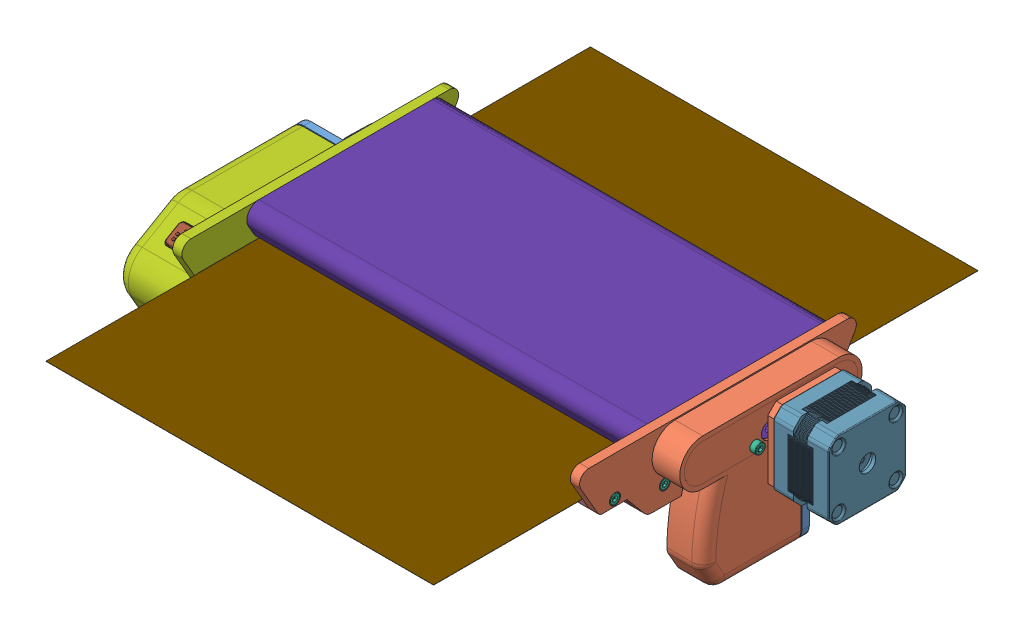
SolidWorks assembly Brailleprinter, configuration Default. Lengths in mm.
Overall size (310 78.25 295).
134 component instances, 36 part files, 16 mates.
Components (placement in the parent):
- Frame-2: Frame [Default] at (6.5066 -52.4976 -87.3723) size (276.5 62.15 134.33)
  - Frame plate-1: Frame plate [Default] at (76.4618 160.0978 166.7235) size (276.5 61.25 5)
  - Linear rail-1: Linear rail [Default] at (70.7618 160.0978 171.7235) x (0 1 0) z (1 0 0) size (9 6.5 208.9)
  - Motor plate-1: Motor plate [Default] at (46.4618 139.3516 166.7235) x (-1 0 0) z (0 0 -1) size (61.5 53.5 20.15)
  - Paper tray-1: Paper tray [Default] at (175.2118 177.0978 267.3903) x (0 0 -1) z (1 0 0) size (134.33 22 210.5)
  - Limit switch-1: Limit switch [Default] at (79.6118 165.8978 235.3903) x (0 0 -1) z (1 0 0) size (20.1 16 6.3)
  - socket head cap screw_din-1: socket head cap screw_din [DIN 912 M3 x 12 --- 12N] at (76.4618 160.0978 177.7235) x (0 0 -1) z (1 0 0) size (15 5.5 5.5)
  - socket head cap screw_din-2: socket head cap screw_din [DIN 912 M3 x 12 --- 12N] at (96.4618 160.0978 177.7235) x (0 0 -1) z (1 0 0) size (15 5.5 5.5)
  - socket head cap screw_din-3: socket head cap screw_din [DIN 912 M3 x 12 --- 12N] at (116.4618 160.0978 177.7235) x (0 0 -1) z (1 0 0) size (15 5.5 5.5)
  - socket head cap screw_din-4: socket head cap screw_din [DIN 912 M3 x 12 --- 12N] at (136.4618 160.0978 177.7235) x (0 0 -1) z (1 0 0) size (15 5.5 5.5)
  - socket head cap screw_din-5: socket head cap screw_din [DIN 912 M3 x 12 --- 12N] at (156.4618 160.0978 177.7235) x (0 0 -1) z (1 0 0) size (15 5.5 5.5)
  - socket head cap screw_din-6: socket head cap screw_din [DIN 912 M3 x 12 --- 12N] at (176.4618 160.0978 177.7235) x (0 0 -1) z (1 0 0) size (15 5.5 5.5)
  - socket head cap screw_din-7: socket head cap screw_din [DIN 912 M3 x 12 --- 12N] at (196.4618 160.0978 177.7235) x (0 0 -1) z (1 0 0) size (15 5.5 5.5)
  - socket head cap screw_din-8: socket head cap screw_din [DIN 912 M3 x 12 --- 12N] at (216.4618 160.0978 177.7235) x (0 0 -1) z (1 0 0) size (15 5.5 5.5)
  - socket head cap screw_din-9: socket head cap screw_din [DIN 912 M3 x 12 --- 12N] at (236.4618 160.0978 177.7235) x (0 0 -1) z (1 0 0) size (15 5.5 5.5)
  - socket head cap screw_din-10: socket head cap screw_din [DIN 912 M3 x 12 --- 12N] at (256.4618 160.0978 177.7235) x (0 0 -1) z (1 0 0) size (15 5.5 5.5)
  - socket head cap screw_din-11: socket head cap screw_din [DIN 912 M3 x 8 --- 8N] at (276.4618 160.0978 177.7235) x (0 0 -1) z (1 0 0) size (11 5.5 5.5)
  - socket head cap screw_din-12: socket head cap screw_din [DIN 912 M3 x 8 --- 8N] at (74.9618 175.3516 154.0735) x (0 -1 0) z (0 0 1) size (11 5.5 5.5)
  - socket head cap screw_din-13: socket head cap screw_din [DIN 912 M3 x 8 --- 8N] at (82.4618 175.3516 154.0735) x (0 -1 0) z (0 0 1) size (11 5.5 5.5)
  - socket head cap screw_din-14: socket head cap screw_din [DIN 912 M3 x 12 --- 12N] at (64.9618 173.5978 257.5035) size (15 5.5 5.5)
  - socket head cap screw_din-15: socket head cap screw_din [DIN 912 M3 x 8 --- 8N] at (64.9618 167.0978 230.5035) size (11 5.5 5.5)
  - socket head cap screw_din-16: socket head cap screw_din [DIN 912 M3 x 12 --- 12N] at (285.4618 167.0978 230.5035) x (-1 0 0) z (0 0.924225 0.381849) size (15 5.5 5.5)
  - socket head cap screw_din-17: socket head cap screw_din [DIN 912 M3 x 12 --- 12N] at (285.4618 173.5978 257.5035) x (-1 0 0) z (0 0.924225 0.381849) size (15 5.5 5.5)
  - socket head cap screw_din-18: socket head cap screw_din [DIN 912 M2.5 x 10 --- 10N] at (73.9618 165.8978 235.3903) size (12.5 4.5 4.5)
  - socket head cap screw_din-19: socket head cap screw_din [DIN 912 M2.5 x 10 --- 10N] at (73.9618 165.8978 225.8903) size (12.5 4.5 4.5)
- Electronic box-1: Electronic box [Default] at (-32.2784 21.5685 22.2017) size (46 78.25 150)
  - Electronic box-1: Electronic box [Default] at (103.7468 101.0355 62.1495) size (46 78.25 150)
  - Main PCB-1: Main PCB [Default] at (71.2468 84.0555 113.6495) x (0 0 -1) z (0 -1 0) size (59.38 19.5 46.8)
  - Button PCB-1: Button PCB [Default] at (70.1673 63.8406 151.7276) x (1 0 0) z (0 0.866025 0.5) size (23 28.25 20.2)
    - Button PCB-1: Button PCB [Default] at (17.5795 4.2128 10.4054) size (22 28 18.6)
    - ButtonF-1: ButtonF [Default] at (24.8295 26.9628 23.0054) x (1 0 0) z (0 -1 0) size (8.5 5.6 11)
    - ButtonS-1: ButtonS [Default] at (10.3295 26.9628 23.0054) x (1 0 0) z (0 -1 0) size (8.5 5.6 11)
  - Speaker-1: Speaker [Default] at (87.7468 61.2855 147.1199) x (0 0.866025 0.5) z (-1 0 0) size (19.8 4.4 19.8)
  - Servo PCB-1: Servo PCB [Default] at (73.2468 46.7855 136.3495) size (25.5 14.5 62.2)
  - Limit switch-1: Limit switch [Default] at (94.7468 80.2855 109.7827) x (0 -1 0) z (0 0 1) size (20.1 16 6.3)
  - socket head cap screw_din-1: socket head cap screw_din [DIN 912 M3 x 6 --- 6N] at (74.2468 60.0355 72.1495) x (-1 0 0) z (0 0.924225 0.381849) size (9 5.5 5.5)
  - socket head cap screw_din-5: socket head cap screw_din [DIN 912 M3 x 6 --- 6N] at (74.2468 92.5355 72.1495) x (-1 0 0) z (0 0.924225 0.381849) size (9 5.5 5.5)
  - socket head cap screw_din-6: socket head cap screw_din [DIN 912 M3 x 6 --- 6N] at (74.2468 92.5355 95.1495) x (-1 0 0) z (0 0.924225 0.381849) size (9 5.5 5.5)
  - socket head cap screw_din-7: socket head cap screw_din [DIN 912 M3 x 5 --- 5N] at (95.7468 51.3855 77.1495) x (0 -1 0) z (0 0 1) size (8 5.5 5.5)
  - socket head cap screw_din-8: socket head cap screw_din [DIN 912 M3 x 5 --- 5N] at (76.2468 51.3855 77.1495) x (0 -1 0) z (0 0 1) size (8 5.5 5.5)
  - socket head cap screw_din-9: socket head cap screw_din [DIN 912 M2 x 12 --- 12N] at (94.7468 70.7855 104.6327) x (0 0 1) z (-1 0 0) size (14 3.8 3.8)
  - socket head cap screw_din-10: socket head cap screw_din [DIN 912 M2 x 12 --- 12N] at (94.7468 80.2855 104.6327) x (0 0 1) z (-1 0 0) size (14 3.8 3.8)
  - socket head cap screw_din-11: socket head cap screw_din [DIN 912 M3 x 12 --- 12N] at (108.7468 82.0658 150.7791) x (-1 0 0) z (0 0.924225 0.381849) size (15 5.5 5.5)
  - socket head cap screw_din-12: socket head cap screw_din [DIN 912 M3 x 8 --- 8N] at (103.4968 42.7855 107.1495) x (0 1 0) z (0 0 1) size (11 5.5 5.5)
  - socket head cap screw_din-13: socket head cap screw_din [DIN 912 M3 x 8 --- 8N] at (103.4968 42.7855 74.1495) x (0 1 0) z (0 0 1) size (11 5.5 5.5)
- Motion system-1: Motion system [Default] at origin size (274.3 42.3 52.5)
  - Stepper motor-1: Stepper motor [Default] at (52.9684 86.854 64.8512) x (1 0 0) z (0 -1 0) size (42.8 48.5 42.3)
  - 2GT driving pulley-1: 2GT driving pulley [20T long] at (52.9684 86.854 78.3512) x (1 0 0) z (0 -1 0) size (16 15.5 16)
  - 2GT driving pulley-2: 2GT driving pulley [20T short] at (294.9684 86.854 84.8512) x (0.57818 -0.815909 0) z (-0.815909 -0.57818 0) size (16 9 16)
  - Belt^Motion system-1: Belt^Motion system [Default] at (47.0093 90.3514 89.3512) size (255.49 13.49 6) (virtual)
  - Shoulder screw-1: Shoulder screw [Default] at (294.9684 86.854 76.3512) x (1 0 0) z (0 -1 0) size (9 22 9)
  - shim-support ring2_din-1: shim-support ring2_din [DIN 988-5x10x0.5] at (294.9684 86.854 84.8512) x (0 0 -1) z (1 0 0) size (0.5 9.81 9.81)
  - shim-support ring2_din-2: shim-support ring2_din [DIN 988-5x10x0.5] at (294.9684 86.854 93.8512) x (0 0 1) z (-1 0 0) size (0.5 9.81 9.81)
  - plain washer grade a_din-1: plain washer grade a_din [Washer DIN 125 - A 3.2] at (68.4684 71.354 86.3512) x (0 0 -1) z (1 0 0) size (0.5 7 7)
  - plain washer grade a_din-2: plain washer grade a_din [Washer DIN 125 - A 3.2] at (37.4684 71.354 86.3512) x (0 0 -1) z (1 0 0) size (0.5 7 7)
  - plain washer grade a_din-3: plain washer grade a_din [Washer DIN 125 - A 3.2] at (68.4684 102.354 86.3512) x (0 0 -1) z (1 0 0) size (0.5 7 7)
  - plain washer grade a_din-4: plain washer grade a_din [Washer DIN 125 - A 3.2] at (37.4684 102.354 86.3512) x (0 0 -1) z (1 0 0) size (0.5 7 7)
  - socket head cap screw_din-1: socket head cap screw_din [DIN 912 M3 x 16 --- 16N] at (68.4684 71.354 89.8512) x (0 0 -1) z (1 0 0) size (19 5.5 5.5)
  - socket head cap screw_din-2: socket head cap screw_din [DIN 912 M3 x 16 --- 16N] at (37.4684 71.354 89.8512) x (0 0 -1) z (1 0 0) size (19 5.5 5.5)
  - socket head cap screw_din-3: socket head cap screw_din [DIN 912 M3 x 16 --- 16N] at (37.4684 102.354 89.8512) x (0 0 -1) z (1 0 0) size (19 5.5 5.5)
  - socket head cap screw_din-4: socket head cap screw_din [DIN 912 M3 x 16 --- 16N] at (68.4684 102.354 89.8512) x (0 0 -1) z (1 0 0) size (19 5.5 5.5)
- Paper feeding-1: Paper feeding [Default] at (66.9072 121.9255 143.2262) x (0 0 -1) z (1 0 0) size (150 78.25 268)
  - Side block-1: Side block [Default] at (58.8749 0.6785 220.0612) size (150 78.25 23.5)
  - MR128ZZ bearing-1: MR128ZZ bearing [Default] at (5.5949 7.5785 7.8112) size (12 12 3.5)
  - MR128ZZ bearing-2: MR128ZZ bearing [Default] at (79.5949 7.5785 7.8112) size (12 12 3.5)
  - MR128ZZ bearing-3: MR128ZZ bearing [Default] at (5.5949 7.5785 221.8112) size (12 12 3.5)
  - MR128ZZ bearing-4: MR128ZZ bearing [Default] at (79.5949 7.5785 221.8112) size (12 12 3.5)
  - Counter block-1: Counter block [Milled holes] at (25.5949 9.1785 5.5612) x (0 -1 0) z (0 0 1) size (12 12 218.5)
  - Driving rod-1: Driving rod [Feed roller] at (5.5949 7.5785 6.0612) size (9.8 9.8 229.5)
  - Driving rod-2: Driving rod [Outfeed roller] at (79.5949 7.5785 235.5612) x (-1 0 0) z (0 0 -1) size (9.89 9.89 229.5)
  - Stepper motor-1: Stepper motor [Default] at (61.3758 -3.9671 254.5612) x (0 -1 0) z (1 0 0) size (42.8 48.5 42.3)
  - 2GT driving pulley-1: 2GT driving pulley [20 short 8mm hole] at (79.5949 7.5785 225.5612) x (1 0 0) z (0 -1 0) size (16 10 16)
  - 2GT driving pulley-2: 2GT driving pulley [20 short 8mm hole] at (5.5949 7.5785 225.5612) x (1 0 0) z (0 -1 0) size (16 10 16)
  - 2GT driving pulley-3: 2GT driving pulley [16T short] at (61.3758 -3.9671 226.0612) x (1 0 0) z (0 -1 0) size (13 9.5 13)
  - HK050908 bearing-1: HK050908 bearing [Default] at (41.8749 4.6647 227.0612) size (9 9 8)
  - Belt^Paper feeding-1: Belt^Paper feeding [Default] at (0 0.2 231.0612) size (87.49 23.76 6) (virtual)
  - Shortened shoulder screw-1: Shortened shoulder screw [Default] at (41.8749 4.6647 222.0612) x (1 0 0) z (0 -1 0) size (9 17 9)
  - socket head cap screw_din-1: socket head cap screw_din [DIN 912 M3 x 12 --- 12N] at (66.8749 -50.5715 230.0612) x (-1 0 0) z (0 0 -1) size (15 5.5 5.5)
  - socket head cap screw_din-2: socket head cap screw_din [DIN 912 M3 x 12 --- 12N] at (66.8749 -19.5715 230.0612) x (-1 0 0) z (0 0 -1) size (15 5.5 5.5)
  - socket head cap screw_din-3: socket head cap screw_din [DIN 912 M3 x 10 --- 10N] at (45.8758 11.5329 234.5612) x (0 0 1) z (-1 0 0) size (13 5.5 5.5)
  - socket head cap screw_din-4: socket head cap screw_din [DIN 912 M3 x 8 --- 8N] at (76.8758 11.5329 236.0612) x (0 0 1) z (-1 0 0) size (11 5.5 5.5)
  - socket head cap screw_din-5: socket head cap screw_din [DIN 912 M3 x 8 --- 8N] at (76.8758 -19.4715 237.0612) x (0 0 1) z (-1 0 0) size (11 5.5 5.5)
  - socket head cap screw_din-6: socket head cap screw_din [DIN 912 M3 x 10 --- 10N] at (45.8749 -19.4715 235.5612) x (0 0 1) z (-1 0 0) size (13 5.5 5.5)
  - socket head cap screw_din-7: socket head cap screw_din [DIN 912 M3 x 12 --- 12N] at (33.9103 1.2819 243.0612) x (0 0 -1) z (1 0 0) size (15 5.5 5.5)
- Carriage-1: Carriage [Default] at (159.9558 79.7282 86.822) size (156.25 52.87 74.72)
  - Carriage-2: Carriage [Default] at (0 41.872 39.3434) x (-1 0 0) z (0 0 1) size (39 46.18 74.72)
  - Servo-4: Servo [Default] at (32.75 29.372 23.6842) x (0 0 -1) z (0 1 0) size (32.3 30.5 12.25)
  - Servo-5: Servo [Default] at (32.75 16.872 26.1842) x (0 0 -1) z (0 1 0) size (32.3 30.5 12.25)
  - Servo-6: Servo [Default] at (32.75 4.372 28.6842) x (0 0 -1) z (0 1 0) size (32.3 30.5 12.25)
  - Servo-7: Servo [Default] at (-32.75 29.372 23.6842) x (0 0 -1) z (0 -1 0) size (32.3 30.5 12.25)
  - Servo-8: Servo [Default] at (-32.75 16.872 26.1842) x (0 0 -1) z (0 -1 0) size (32.3 30.5 12.25)
  - Servo-9: Servo [Default] at (-32.75 4.372 28.6842) x (0 0 -1) z (0 -1 0) size (32.3 30.5 12.25)
  - Servo arm-1: Servo arm [Mirrored] at (-4 4.372 23.4342) x (0 0 1) z (0 1 0) size (14.5 4.25 7)
  - Servo arm-2: Servo arm [Mirrored] at (-4 16.872 20.9342) x (0 0 1) z (0 1 0) size (14.5 4.25 7)
  - Servo arm-3: Servo arm [Mirrored] at (-4 29.372 18.4342) x (0 0 1) z (0 1 0) size (14.5 4.25 7)
  - Printhead insert-3: Printhead insert [Default] at (0 42.872 24.9592) x (-1 0 0) z (0 0 1) size (15 10 17.72)
  - Pin-2: Pin [l=7.5] at (1.25 45.372 28.3092) x (1 0 0) z (0 0 -1) size (2.5 15 2.5)
  - Pin-4: Pin [l=20] at (1.25 45.372 30.8092) x (1 0 0) z (0 0 -1) size (2.5 27.5 2.5)
  - Pin-5: Pin [l=32.5] at (1.25 45.372 33.3092) x (1 0 0) z (0 0 -1) size (2.5 40 2.5)
  - Pin-6: Pin [l=7.5] at (-1.25 45.372 28.3092) x (-1 0 0) z (0 0 1) size (2.5 15 2.5)
  - Pin-7: Pin [l=20] at (-1.25 45.372 30.8092) x (-1 0 0) z (0 0 1) size (2.5 27.5 2.5)
  - Pin-8: Pin [l=32.5] at (-1.25 45.372 33.3092) x (-1 0 0) z (0 0 1) size (2.5 40 2.5)
  - Linear block-1: Linear block [Default] at (0 27.872 -0.4708) x (0 1 0) z (1 0 0) size (20 8 30.3)
  - Servo arm-8: Servo arm [Default] at (-4.5 29.372 18.4342) x (0 0 1) z (0 1 0) size (14.5 4.25 7)
  - Servo arm-9: Servo arm [Default] at (-4.5 16.872 20.9342) x (0 0 1) z (0 1 0) size (14.5 4.25 7)
  - Servo arm-10: Servo arm [Default] at (-4.5 4.372 23.4342) x (0 0 1) z (0 1 0) size (14.5 4.25 7)
  - Cable carrier-1: Cable carrier [Default] at (-10 13.872 -20.1208) x (-1 0 0) z (0 1 0) size (156.25 15 26.25)
  - Spring-1: Spring [Default] at (1.25 37.972 28.3092) size (2.04 5.02 2.08)
  - Spring-4: Spring [Default] at (-1.25 37.972 28.3092) size (2.04 5.02 2.08)
  - Spring-2: Spring [Default] at (1.25 37.972 30.8092) size (2.04 5.02 2.08)
  - Spring-5: Spring [Default] at (-1.25 37.972 30.8092) size (2.04 5.02 2.08)
  - Spring-3: Spring [Default] at (1.25 37.972 33.3092) size (2.04 5.02 2.08)
  - Spring-6: Spring [Default] at (-1.25 37.972 33.3092) size (2.04 5.02 2.08)
  - socket head cap screw_din-1: socket head cap screw_din [DIN 912 M2 x 6 --- 6N] at (-18 4.372 42.4342) size (8 3.8 3.8)
  - socket head cap screw_din-2: socket head cap screw_din [DIN 912 M2 x 6 --- 6N] at (-18 16.872 39.9342) size (8 3.8 3.8)
  - socket head cap screw_din-3: socket head cap screw_din [DIN 912 M2 x 6 --- 6N] at (-18 29.372 37.4342) size (8 3.8 3.8)
  - socket head cap screw_din-4: socket head cap screw_din [DIN 912 M2 x 6 --- 6N] at (-18 4.372 14.9342) size (8 3.8 3.8)
  - socket head cap screw_din-5: socket head cap screw_din [DIN 912 M2 x 6 --- 6N] at (-18 16.872 12.4342) size (8 3.8 3.8)
  - socket head cap screw_din-6: socket head cap screw_din [DIN 912 M2 x 6 --- 6N] at (-18 29.372 9.9342) size (8 3.8 3.8)
  - socket head cap screw_din-13: socket head cap screw_din [DIN 912 M3 x 6 --- 6N] at (-5 20.372 14.2092) x (0 0 -1) z (1 0 0) size (9 5.5 5.5)
  - socket head cap screw_din-14: socket head cap screw_din [DIN 912 M3 x 5 --- 5N] at (-5 35.372 13.2092) x (0 0 -1) z (1 0 0) size (8 5.5 5.5)
  - socket head cap screw_din-17: socket head cap screw_din [DIN 912 M3 x 25 --- 18N] at (-4 7.872 -12.4708) x (0 0 1) z (-1 0 0) size (28 5.5 5.5)
  - socket head cap screw_din-18: socket head cap screw_din [DIN 912 M3 x 5 --- 5N] at (-6.5 17.1262 -20.1208) x (0 -1 0) z (0 0 1) size (8 5.5 5.5)
  - socket head cap screw_din-19: socket head cap screw_din [DIN 912 M3 x 5 --- 5N] at (0.5 17.1262 -20.1208) x (0 -1 0) z (0 0 1) size (8 5.5 5.5)
  - socket head cap screw_din-7: socket head cap screw_din [DIN 912 M2 x 6 --- 6N] at (18 4.372 14.9342) x (-1 0 0) z (0 0 -1) size (8 3.8 3.8)
  - socket head cap screw_din-8: socket head cap screw_din [DIN 912 M2 x 6 --- 6N] at (18 16.872 12.4342) x (-1 0 0) z (0 0 -1) size (8 3.8 3.8)
  - socket head cap screw_din-9: socket head cap screw_din [DIN 912 M2 x 6 --- 6N] at (18 29.372 9.9342) x (-1 0 0) z (0 0 -1) size (8 3.8 3.8)
  - socket head cap screw_din-10: socket head cap screw_din [DIN 912 M2 x 6 --- 6N] at (18 29.372 37.4342) x (-1 0 0) z (0 0 -1) size (8 3.8 3.8)
  - socket head cap screw_din-11: socket head cap screw_din [DIN 912 M2 x 6 --- 6N] at (18 16.872 39.9342) x (-1 0 0) z (0 0 -1) size (8 3.8 3.8)
  - socket head cap screw_din-12: socket head cap screw_din [DIN 912 M2 x 6 --- 6N] at (18 4.372 42.4342) x (-1 0 0) z (0 0 -1) size (8 3.8 3.8)
  - socket head cap screw_din-22: socket head cap screw_din [DIN 912 M3 x 6 --- 6N] at (5 20.372 14.2092) x (0 0 -1) z (1 0 0) size (9 5.5 5.5)
  - socket head cap screw_din-20: socket head cap screw_din [DIN 912 M3 x 5 --- 5N] at (5 35.372 13.2092) x (0 0 -1) z (1 0 0) size (8 5.5 5.5)
- Cap-1: Cap [Default] at (76.4684 127.104 149.9406) x (0 0 -1) z (1 0 0) size (107 15.5 210.5)
- Paper-1: Paper [Default] at (286.7184 124.6002 -31.792) x (-1 0 0) z (0 0 -1) size (210 0.1 295)
Mates (geometry in assembly coordinates):
- Concentric2: concentric aligned: cylinder of Frame-2/Frame plate-1 through (68.4684 71.354 84.3512) axis (0 0 -1) radius 1.5; cylinder of Electronic box-1/Electronic box-1 through (68.4684 71.354 86.3512) axis (0 0 -1) radius 1.6
- Coincident2: coincident anti-aligned: plane of Frame-2/Frame plate-1 through (280.4684 91.1002 84.3512) normal (0 0 1); plane of Electronic box-1/Electronic box-1 through (76.4684 125.604 84.3512) normal (0 0 -1)
- Concentric16: concentric anti-aligned: cylinder of Electronic box-1/Electronic box-1 through (72.4684 129.504 137.6312) axis (1 0 0) radius 6; cylinder of Paper feeding-1/Bearing-1 through (72.9684 129.504 137.6312) axis (-1 0 0) radius 6
- Coincident16: coincident aligned: plane of Electronic box-1/Electronic box-1 through (76.4684 125.104 180.0211) normal (1 0 0); plane of Paper feeding-1/Bearing-1 through (76.4684 129.504 132.1312) normal (1 0 0)
- Coincident17: coincident anti-aligned: plane of Frame-2/MotorPlate-1 through (82.4684 90.604 75.8512) normal (0 0 -1); plane of Assem1^Brailleprinter-1/Stepper motor-1 through (52.9684 86.854 75.8512) normal (0 0 1)
- Concentric18: concentric anti-aligned: cylinder of Electronic box-1/Electronic box-1 through (68.4684 71.354 86.3512) axis (0 0 -1) radius 1.6; cylinder of Assem1^Brailleprinter-1/Stepper motor-1 through (68.4684 71.354 70.8512) axis (0 0 1) radius 1.25
- Coincident30: coincident anti-aligned: plane of Frame-2/Frame plate-1 through (280.4684 91.1002 84.3512) normal (0 0 1); plane of Paper feeding-1/Side block-1 through (291.9684 122.604 84.3512) normal (0 0 -1)
- Concentric35: concentric aligned: cylinder of Frame-2/Frame plate-1 through (296.9684 71.354 84.3512) axis (0 0 -1) radius 1.5; cylinder of Paper feeding-1/Side block-1 through (296.9684 71.354 94.3512) axis (0 0 -1) radius 1.375
- Coincident31: coincident anti-aligned: plane of Frame-2/Linear rail-1 through (286.1684 103.5002 90.8512) normal (0 0 1); plane of Carriage-1/Linear block-1 through (169.4058 111.7002 90.8512) normal (0 0 -1)
- Coincident32: coincident anti-aligned: plane of Frame-2/Linear rail-1 through (286.1684 103.1002 84.7512) normal (0 -1 0); plane of Carriage-1/Linear block-1 through (169.4058 103.1002 86.3512) normal (0 1 0)
- LimitDistance1: limit distance = 68.2375 mm aligned: plane of Frame-2/Linear rail-1 through (77.2684 111.9702 87.8592) normal (-1 0 0); plane of Carriage-1/Linear block-1 through (145.5058 103.2302 87.8592) normal (-1 0 0)
- Coincident33: coincident anti-aligned: plane of Paper feeding-1/Counter block-1 through (290.9684 137.104 113.6312) normal (0 1 0); plane of Cap-1 through (286.9684 137.104 123.6812) normal (0 -1 0)
- Coincident34: coincident anti-aligned: plane of Electronic box-1/Electronic box-1 through (76.4684 125.104 180.0211) normal (1 0 0); plane of Cap-1 through (76.4684 136.104 147.6312) normal (-1 0 0)
- Width1: width anti-aligned: plane of Cap-1 through (286.9684 127.104 123.6812) normal (0 0 -1); plane of Cap-1 through (286.9684 127.104 111.5812) normal (0 0 1); plane of Paper feeding-1/Counter block-1 through (290.9684 135.104 123.6312) normal (0 0 1); plane of Paper feeding-1/Counter block-1 through (290.9684 135.104 111.6312) normal (0 0 -1)
- Width3: width anti-aligned: plane of Paper feeding-1/Counter block-1 through (290.9684 135.104 113.6312) normal (1 0 0); plane of Paper-1 through (72.4684 135.104 113.6312) normal (-1 0 0); plane of Paper feeding-1/Counter block-1 through (76.7184 124.7002 -31.792) normal (-1 0 0); plane of Paper-1 through (286.7184 124.7002 -31.792) normal (1 0 0)
- Coincident35: coincident anti-aligned: plane of Frame-2/Paper tray-1 through (286.9684 124.6002 180.018) normal (0 1 0); plane of Paper-1 through (286.7184 124.6002 -31.792) normal (0 -1 0)
